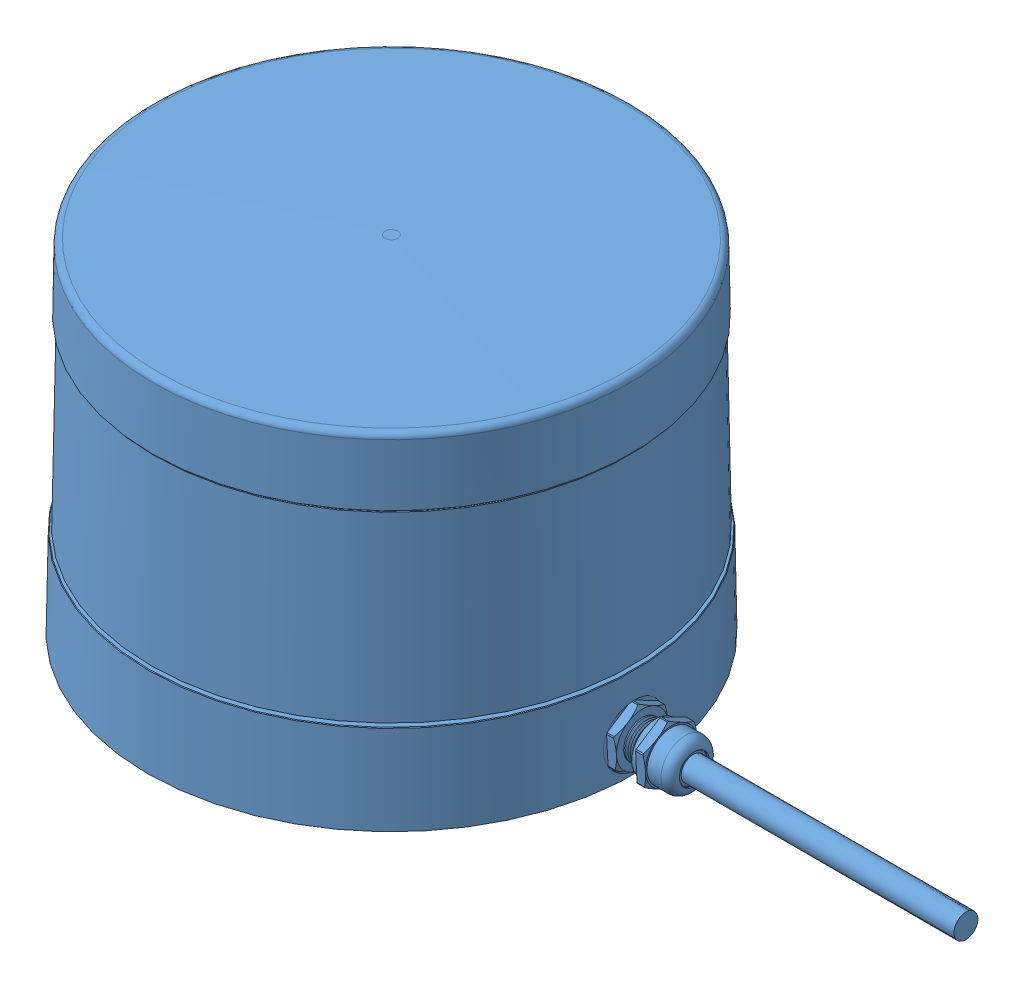
SolidWorks assembly Assem1, configuration Default. Lengths in mm.
Overall size (173.02 72.75 103.27).
2 component instances, 2 part files, 0 mates.
Components (placement in the parent):
- 86-0101 REV B ENVELOPE, VLP-16-1: 86-0101 REV B ENVELOPE, VLP-16 [Default] at (84.0265 90.5634 174.0101) size (173.02 72.75 103.27)
- spanband-1: spanband [Default] at (29.3536 -49.3111 221.0225)
